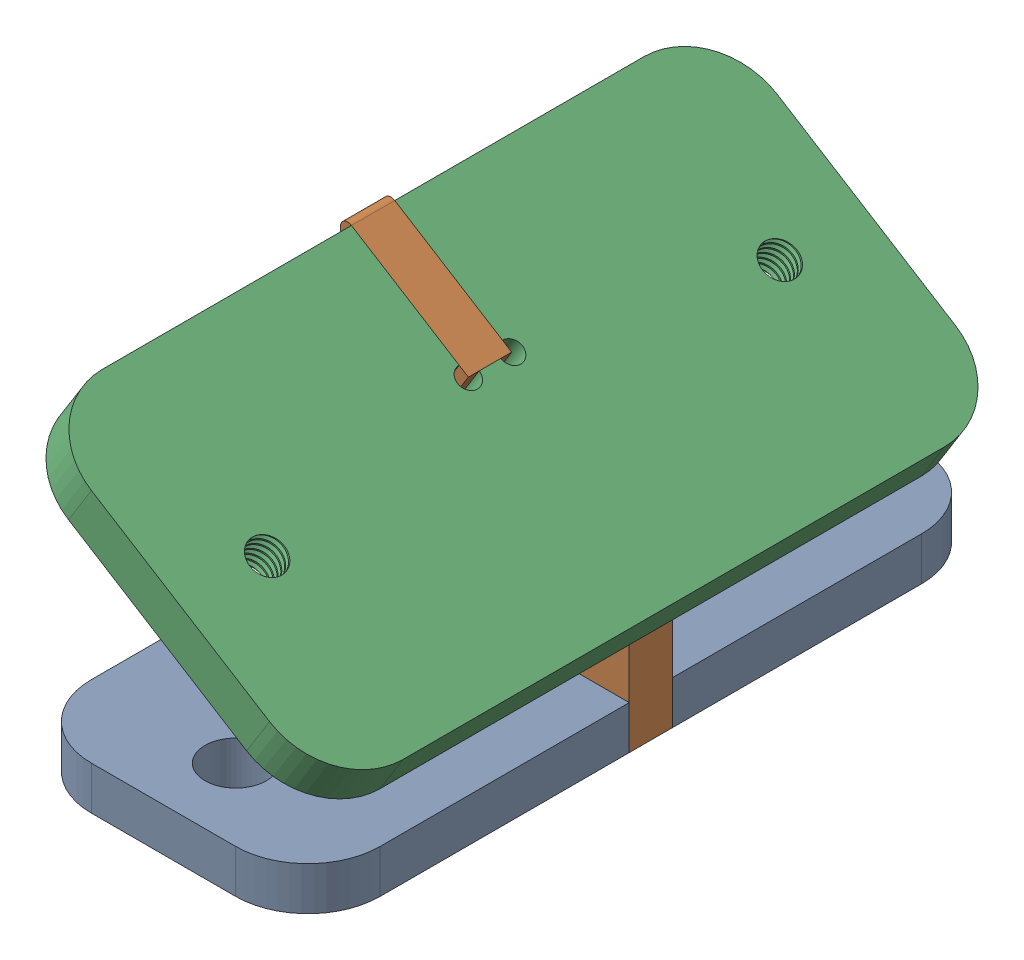
SolidWorks assembly SPR-V1 1000.05-A Hood mounting bracket, configuration Default. Lengths in mm.
Overall size (44.82 44.14 95).
3 component instances, 3 part files, 0 mates.
Components (placement in the parent):
- SPR-V1 1000.05-A Hood bracket 1-1: SPR-V1 1000.05-A Hood bracket 1 [Default] at (0 120 0) x (1 0 0) z (0 1 0) size (40 95 6)
- SPR-V1 1000.05-A Hood bracket 2-1: SPR-V1 1000.05-A Hood bracket 2 [Default] at (0 0 -347.5) size (40 44.14 6)
- SPR-V1 1000.05-A Hood bracket 3-1: SPR-V1 1000.05-A Hood bracket 3 [Default] at (0 0 -347.5) size (44.82 31.06 95)
